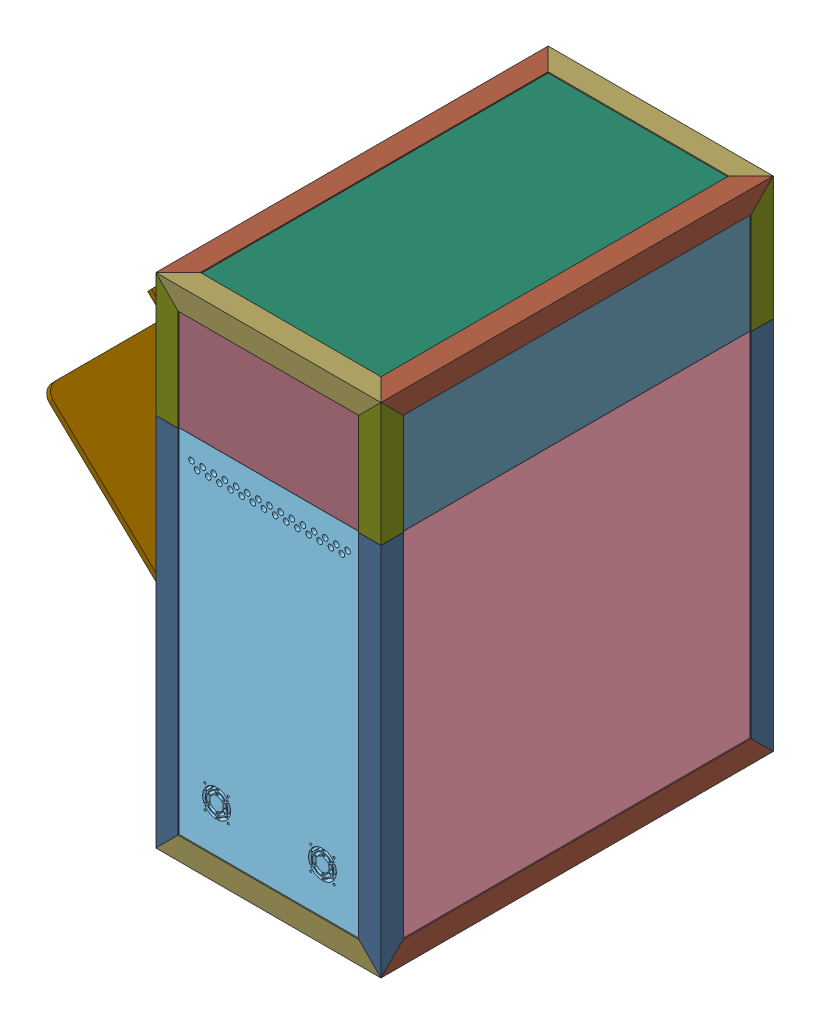
SolidWorks assembly carcasse, configuration Défaut. Lengths in mm.
Overall size (750.58 894.35 704).
60 component instances, 17 part files, 82 mates.
Components (placement in the parent):
- cadre_600x300mm-1: cadre_600x300mm [Défaut] at (-215.194 -19.8636 -400) size (380 40 680)
  - prof_40x40x600mm-1: prof_40x40x600mm [Défaut] at (-14.8937 4.0689 600) size (40 40 600)
  - Rexroth-Default-1: Rexroth-Default [Default] at (-14.8937 24.0689 720) x (0 -1 0) z (-1 0 0) size (40 40 40)
  - prof_40x40x600mm-3: prof_40x40x600mm [Défaut] at (325.1063 4.0689 600) size (40 40 600)
  - Rexroth-Default-3: Rexroth-Default [Default] at (-14.8937 24.0689 80) x (0 -1 0) z (0 0 -1) size (40 40 40)
  - Rexroth-Default-4: Rexroth-Default [Default] at (325.1063 24.0689 80) x (0 -1 0) z (1 0 0) size (40 40 40)
  - Rexroth-Default-5: Rexroth-Default [Default] at (325.1063 24.0689 720) x (0 -1 0) z (0 0 1) size (40 40 40)
  - prof_40x40x300mm-1: prof_40x40x300mm [Défaut] at (105.1063 4.0689 720) x (0 0 1) z (-1 0 0) size (40 40 300)
  - prof_40x40x300mm-2: prof_40x40x300mm [Défaut] at (105.1063 4.0689 80) x (0 0 1) z (-1 0 0) size (40 40 300)
- prof_40x40x600mm-1: prof_40x40x600mm [Défaut] at (109.9123 104.2053 -320) x (1 0 0) z (0 -1 0) size (40 40 600)
- prof_40x40x600mm-2: prof_40x40x600mm [Défaut] at (109.9123 104.2053 320) x (1 0 0) z (0 -1 0) size (40 40 600)
- prof_40x40x600mm-3: prof_40x40x600mm [Défaut] at (-230.0877 104.2053 320) x (1 0 0) z (0 -1 0) size (40 40 600)
- prof_40x40x600mm-4: prof_40x40x600mm [Défaut] at (-230.0877 104.2053 -320) x (1 0 0) z (0 -1 0) size (40 40 600)
- cadre_600x300mm-2: cadre_600x300mm [Défaut] at (95.0186 628.2742 -400) x (-1 0 0) z (0 0 1) size (380 40 680)
  - prof_40x40x600mm-1: prof_40x40x600mm [Défaut] at (-14.8937 4.0689 600) size (40 40 600)
  - Rexroth-Default-1: Rexroth-Default [Default] at (-14.8937 24.0689 720) x (0 -1 0) z (-1 0 0) size (40 40 40)
  - prof_40x40x600mm-3: prof_40x40x600mm [Défaut] at (325.1063 4.0689 600) size (40 40 600)
  - Rexroth-Default-3: Rexroth-Default [Default] at (-14.8937 24.0689 80) x (0 -1 0) z (0 0 -1) size (40 40 40)
  - Rexroth-Default-4: Rexroth-Default [Default] at (325.1063 24.0689 80) x (0 -1 0) z (1 0 0) size (40 40 40)
  - Rexroth-Default-5: Rexroth-Default [Default] at (325.1063 24.0689 720) x (0 -1 0) z (0 0 1) size (40 40 40)
  - prof_40x40x300mm-1: prof_40x40x300mm [Défaut] at (105.1063 4.0689 720) x (0 0 1) z (-1 0 0) size (40 40 300)
  - prof_40x40x300mm-2: prof_40x40x300mm [Défaut] at (105.1063 4.0689 80) x (0 0 1) z (-1 0 0) size (40 40 300)
- prof_40x40x600mm-5: prof_40x40x600mm [Défaut] at (109.9123 134.2053 200) size (40 40 600)
- prof_40x40x600mm-6: prof_40x40x600mm [Défaut] at (-230.0877 134.2053 200) size (40 40 600)
- plaque_acrylique_680x670-2: plaque_acrylique_680x670 [Défaut] at (129.9123 299.2053 0) x (0 0 -1) z (1 0 0) size (680 670 10)
- plaque_acrylique_380x670-1: plaque_acrylique_380x670 [Défaut] at (-60.0877 299.2053 -350) size (380 670 10)
- plaque_acrylique_380x670-2: plaque_acrylique_380x670 [Défaut] at (-60.0877 299.2053 340) size (380 670 10)
- plaque_acrylique_680x670_porte-1: plaque_acrylique_680x670_porte [Défaut] at (-260.0877 299.2053 0) x (0 0 -1) z (1 0 0) size (680 670 10)
- charniere-1: charniere [Défaut] at (-253.7309 154.2053 256.2875) x (0 0 1) z (0 -1 0) size (40 29.08 53.23)
  - axe charnière-1: axe charnière [Défaut] at (-76.2875 9.8568 0) size (40 5 5)
  - batant charnière-1: batant charnière [Défaut] at (-76.2875 10.1991 -17.6196) size (40 7 33.5)
  - batant charnière-2: batant charnière [Défaut] at (-36.2875 -2.6626 12.4029) x (-1 0 0) z (0 0.723942 -0.689861) size (40 7 33.5)
- charniere-2: charniere [Défaut] at (-253.7309 154.2053 -143.7125) x (0 0 1) z (0 -1 0) size (40 29.08 53.23)
  - axe charnière-1: axe charnière [Défaut] at (-76.2875 9.8568 0) size (40 5 5)
  - batant charnière-1: batant charnière [Défaut] at (-76.2875 10.1991 -17.6196) size (40 7 33.5)
  - batant charnière-2: batant charnière [Défaut] at (-36.2875 -2.6626 12.4029) x (-1 0 0) z (0 0.723942 -0.689861) size (40 7 33.5)
- porte-1: porte [Défaut] at (-366.1448 256.769 0) x (0 0 -1) z (0.689861 0.723942 0) size (480 480 10)
- eclisse_40x40x670_bisote_x1-1: eclisse_40x40x670_bisote_x1 [Défaut] at (-242.0877 -37.7947 -331.8864) size (40 672 40)
- eclisse_40x40x670_bisote_x1-2: eclisse_40x40x670_bisote_x1 [Défaut] at (-241.9741 -37.7947 332) x (0 0 -1) z (1 0 0) size (40 672 40)
- eclisse_40x40x670_bisote_x1-3: eclisse_40x40x670_bisote_x1 [Défaut] at (121.9123 -37.7947 331.8864) x (-1 0 0) z (0 0 -1) size (40 672 40)
- eclisse_40x40x670_bisote_x1-4: eclisse_40x40x670_bisote_x1 [Défaut] at (121.7986 -37.7947 -332) x (0 0 1) z (-1 0 0) size (40 672 40)
- eclisse_40x40x704_bisote_x2-1: eclisse_40x40x704_bisote_x2 [Défaut] at (121.7986 -17.7947 352) x (0 1 0) z (-1 0 0) size (40 704 40)
- eclisse_40x40x704_bisote_x2-2: eclisse_40x40x704_bisote_x2 [Défaut] at (-242.0877 -17.681 352) x (1 0 0) z (0 1 0) size (40 704 40)
- eclisse_40x40x404_bisote_x2-1: eclisse_40x40x404_bisote_x2 [Défaut] at (141.9123 -17.681 332) x (0 0 -1) z (0 1 0) size (40 404 40)
- eclisse_40x40x404_bisote_x2-2: eclisse_40x40x404_bisote_x2 [Défaut] at (141.9123 -17.7947 -331.8864) x (0 1 0) z (0 0 1) size (40 404 40)
- couvercle-1: couvercle [Défaut] at (127.4119 748.2742 345) size (404 222 704)
  - plaque_acrylique_380x210-1: plaque_acrylique_380x210 [Défaut] at (-187.4996 -8.7215 -5) size (380 210 10)
  - plaque_acrylique_680x210-1: plaque_acrylique_680x210 [Défaut] at (2.5004 -8.7215 -345) x (0 0 -1) z (1 0 0) size (680 210 10)
  - plaque_acrylique_680x210-2: plaque_acrylique_680x210 [Défaut] at (-387.4996 -8.7215 -345) x (0 0 -1) z (1 0 0) size (680 210 10)
  - plaque_acrylique_380x210-2: plaque_acrylique_380x210 [Défaut] at (-187.4996 -8.7215 -695) size (380 210 10)
  - plaque_acrylique_380x680-1: plaque_acrylique_380x680 [Défaut] at (-187.4996 96.2785 -345) x (1 0 0) z (0 1 0) size (380 680 10)
  - eclisse_40x40x404_bisote_x2-1: eclisse_40x40x404_bisote_x2 [Défaut] at (14.5004 88.1649 -677) x (0 0 1) z (0 -1 0) size (40 404 40)
  - eclisse_40x40x704_bisote_x2-1: eclisse_40x40x704_bisote_x2 [Défaut] at (-5.6132 88.2785 -697) x (0 -1 0) z (-1 0 0) size (40 704 40)
  - eclisse_40x40x404_bisote_x2-2: eclisse_40x40x404_bisote_x2 [Défaut] at (-389.4996 88.1649 -13) x (0 0 -1) z (0 -1 0) size (40 404 40)
  - eclisse_40x40x704_bisote_x2-2: eclisse_40x40x704_bisote_x2 [Défaut] at (-369.4996 88.1649 -697) x (1 0 0) z (0 -1 0) size (40 704 40)
  - eclisse_40x40x222_bisote_x1-1: eclisse_40x40x222_bisote_x1 [Défaut] at (-369.386 108.2785 -677) x (0 0 1) z (1 0 0) size (40 222 40)
  - eclisse_40x40x222_bisote_x1-2: eclisse_40x40x222_bisote_x1 [Défaut] at (-5.4996 108.2785 -676.8864) x (-1 0 0) z (0 0 1) size (40 222 40)
  - eclisse_40x40x222_bisote_x1-3: eclisse_40x40x222_bisote_x1 [Défaut] at (-5.6132 108.2785 -13) x (0 0 -1) z (-1 0 0) size (40 222 40)
  - eclisse_40x40x222_bisote_x1-4: eclisse_40x40x222_bisote_x1 [Défaut] at (-369.4996 108.2785 -13.1136) x (1 0 0) z (0 0 -1) size (40 222 40)
- plaque_repartition_aire_chaud_300x544mm-1: plaque_repartition_aire_chaud_300x544mm [Défaut] at (-60.0936 129.2053 0) x (0 0 -1) z (1 0 0) size (680 10 324)
Mates (geometry in assembly coordinates):
- Coïncidente1: coincident anti-aligned: plane of cadre_600x300mm-1/Rexroth-Default-3 through (-230.0877 4.2053 -320) normal (0 1 0); plane of prof_40x40x600mm-4 through (-213.0877 4.2053 -337) normal (0 -1 0)
- Coïncidente2: coincident anti-aligned: plane of cadre_600x300mm-1/Rexroth-Default-1 through (-230.0877 4.2053 320) normal (0 1 0); plane of prof_40x40x600mm-3 through (-213.0877 4.2053 303) normal (0 -1 0)
- Coïncidente3: coincident anti-aligned: plane of cadre_600x300mm-1/Rexroth-Default-5 through (109.9123 4.2053 320) normal (0 1 0); plane of prof_40x40x600mm-2 through (126.9123 4.2053 303) normal (0 -1 0)
- Coïncidente4: coincident anti-aligned: plane of cadre_600x300mm-1/Rexroth-Default-4 through (109.9123 4.2053 -320) normal (0 1 0); plane of prof_40x40x600mm-1 through (126.9123 4.2053 -337) normal (0 -1 0)
- Coïncidente5: coincident aligned: plane of cadre_600x300mm-1/Rexroth-Default-4 through (129.9123 -15.7947 -320) normal (1 0 0); plane of prof_40x40x600mm-1 through (129.9123 604.2053 -314) normal (1 0 0)
- Coïncidente6: coincident aligned: plane of cadre_600x300mm-1/Rexroth-Default-4 through (109.9123 -15.7947 -340) normal (0 0 -1); plane of prof_40x40x600mm-1 through (115.9123 604.2053 -340) normal (0 0 -1)
- Coïncidente7: coincident aligned: plane of cadre_600x300mm-1/Rexroth-Default-5 through (129.9123 -15.7947 320) normal (1 0 0); plane of prof_40x40x600mm-2 through (129.9123 604.2053 303) normal (1 0 0)
- Coïncidente8: coincident aligned: plane of cadre_600x300mm-1/Rexroth-Default-5 through (109.9123 -15.7947 340) normal (0 0 1); plane of prof_40x40x600mm-2 through (126.9123 604.2053 340) normal (0 0 1)
- Coïncidente9: coincident aligned: plane of cadre_600x300mm-1/Rexroth-Default-1 through (-230.0877 -15.7947 340) normal (0 0 1); plane of prof_40x40x600mm-3 through (-213.0877 604.2053 340) normal (0 0 1)
- Coïncidente10: coincident aligned: plane of cadre_600x300mm-1/Rexroth-Default-1 through (-250.0877 -15.7947 320) normal (-1 0 0); plane of prof_40x40x600mm-3 through (-250.0877 604.2053 337) normal (-1 0 0)
- Coïncidente11: coincident aligned: plane of cadre_600x300mm-1/Rexroth-Default-3 through (-250.0877 -15.7947 -320) normal (-1 0 0); plane of prof_40x40x600mm-4 through (-250.0877 604.2053 -303) normal (-1 0 0)
- Coïncidente12: coincident aligned: plane of cadre_600x300mm-1/Rexroth-Default-3 through (-230.0877 -15.7947 -340) normal (0 0 -1); plane of prof_40x40x600mm-4 through (-247.0877 604.2053 -340) normal (0 0 -1)
- Coïncidente13: coincident anti-aligned: plane of prof_40x40x600mm-1 through (126.9123 604.2053 -337) normal (0 1 0); plane of cadre_600x300mm-2/Rexroth-Default-3 through (109.9123 604.2053 -320) normal (0 -1 0)
- Coïncidente14: coincident aligned: plane of prof_40x40x600mm-3 through (-250.0877 604.2053 337) normal (-1 0 0); plane of cadre_600x300mm-2/Rexroth-Default-5 through (-250.0877 624.2053 320) normal (-1 0 0)
- Coïncidente15: coincident aligned: plane of prof_40x40x600mm-3 through (-236.0877 604.2053 340) normal (0 0 1); plane of cadre_600x300mm-2/Rexroth-Default-5 through (-230.0877 624.2053 340) normal (0 0 1)
- Coïncidente16: coincident anti-aligned: plane of prof_40x40x600mm-4 through (-236.0877 604.2053 -300) normal (0 0 1); plane of prof_40x40x600mm-6 through (-213.0877 117.2053 -300) normal (0 0 -1)
- Coïncidente17: coincident aligned: plane of prof_40x40x600mm-4 through (-250.0877 604.2053 -303) normal (-1 0 0); plane of prof_40x40x600mm-6 through (-250.0877 151.2053 -300) normal (-1 0 0)
- Distance1: distance = 110 mm anti-aligned: plane of prof_40x40x600mm-6 through (-247.0877 114.2053 -300) normal (0 -1 0); plane of cadre_600x300mm-1/prof_40x40x600mm-1 through (-236.0877 4.2053 -300) normal (0 1 0)
- Coïncidente19: coincident aligned: plane of prof_40x40x600mm-1 through (129.9123 604.2053 -314) normal (1 0 0); plane of prof_40x40x600mm-5 through (129.9123 140.2053 -300) normal (1 0 0)
- Coïncidente20: coincident anti-aligned: plane of prof_40x40x600mm-1 through (126.9123 604.2053 -300) normal (0 0 1); plane of prof_40x40x600mm-5 through (126.9123 117.2053 -300) normal (0 0 -1)
- Coïncidente21: coincident aligned: plane of prof_40x40x600mm-5 through (103.9123 154.2053 -300) normal (0 1 0); plane of prof_40x40x600mm-6 through (-213.0877 154.2053 -300) normal (0 1 0)
- Coïncidente22: coincident anti-aligned: plane of prof_40x40x600mm-5 through (89.9123 151.2053 -300) normal (-1 0 0); plane of ? through (89.9123 117.2053 -297) normal (1 0 0)
- Coïncidente23: coincident aligned: plane of prof_40x40x600mm-5 through (103.9123 154.2053 -300) normal (0 1 0); plane of ? through (-210.0877 154.2053 -274) normal (0 1 0)
- Coïncidente24: coincident anti-aligned: plane of prof_40x40x600mm-1 through (103.9123 604.2053 -300) normal (0 0 1); plane of ? through (-210.0877 140.2053 -300) normal (0 0 -1)
- Coïncidente29: coincident aligned: plane of ? through (-210.0877 154.2053 -103.667) normal (0 1 0); plane of prof_40x40x600mm-5 through (103.9123 154.2053 -300) normal (0 1 0)
- Coïncidente31: coincident anti-aligned: plane of ? through (89.9123 117.2053 -103.667) normal (1 0 0); plane of prof_40x40x600mm-5 through (89.9123 151.2053 -300) normal (-1 0 0)
- Distance2: distance = 153.333 mm anti-aligned: plane of ? through (-210.0877 140.2053 -106.667) normal (0 0 -1); plane of ? through (-210.0877 151.2053 -260) normal (0 0 1)
- Coïncidente34: coincident anti-aligned: plane of cadre_600x300mm-2/prof_40x40x600mm-3 through (-250.0877 641.2053 -300) normal (-1 0 0); plane of plaque_acrylique_680x670_porte-1 through (-250.0877 299.2053 0) normal (1 0 0)
- Coïncidente36: coincident aligned: plane of cadre_600x300mm-1/prof_40x40x600mm-1 through (-247.0877 -35.7947 -300) normal (0 -1 0); plane of plaque_acrylique_680x670_porte-1 through (-250.0877 -35.7947 340) normal (0 -1 0)
- Coïncidente37: coincident aligned: plane of prof_40x40x600mm-3 through (-236.0877 604.2053 340) normal (0 0 1); plane of plaque_acrylique_680x670_porte-1 through (-250.0877 634.2053 340) normal (0 0 1)
- Coïncidente38: coincident anti-aligned: plane of cadre_600x300mm-2/prof_40x40x600mm-1 through (129.9123 630.2053 -300) normal (1 0 0); plane of plaque_acrylique_680x670-2 through (129.9123 299.2053 0) normal (-1 0 0)
- Coïncidente39: coincident aligned: plane of prof_40x40x600mm-2 through (126.9123 604.2053 340) normal (0 0 1); plane of plaque_acrylique_680x670-2 through (139.9123 634.2053 340) normal (0 0 1)
- Coïncidente40: coincident aligned: plane of cadre_600x300mm-1/prof_40x40x600mm-3 through (115.9123 -35.7947 -300) normal (0 -1 0); plane of plaque_acrylique_680x670-2 through (139.9123 -35.7947 340) normal (0 -1 0)
- Coïncidente41: coincident anti-aligned: plane of prof_40x40x600mm-3 through (-213.0877 604.2053 340) normal (0 0 1); plane of plaque_acrylique_380x670-2 through (-60.0877 299.2053 340) normal (0 0 -1)
- Coïncidente42: coincident aligned: plane of cadre_600x300mm-2/Rexroth-Default-5 through (-250.0877 624.2053 320) normal (-1 0 0); plane of plaque_acrylique_380x670-2 through (-250.0877 634.2053 350) normal (-1 0 0)
- Coïncidente43: coincident aligned: plane of cadre_600x300mm-1/prof_40x40x300mm-1 through (89.9123 -35.7947 326) normal (0 -1 0); plane of plaque_acrylique_380x670-2 through (-250.0877 -35.7947 350) normal (0 -1 0)
- Coïncidente44: coincident aligned: plane of cadre_600x300mm-1/prof_40x40x300mm-2 through (89.9123 -35.7947 -337) normal (0 -1 0); plane of plaque_acrylique_380x670-1 through (-250.0877 -35.7947 -340) normal (0 -1 0)
- Coïncidente45: coincident aligned: plane of cadre_600x300mm-2/Rexroth-Default-4 through (-250.0877 624.2053 -320) normal (-1 0 0); plane of plaque_acrylique_380x670-1 through (-250.0877 634.2053 -340) normal (-1 0 0)
- Coïncidente46: coincident anti-aligned: plane of prof_40x40x600mm-4 through (-247.0877 604.2053 -340) normal (0 0 -1); plane of plaque_acrylique_380x670-1 through (-60.0877 299.2053 -340) normal (0 0 1)
- Coïncidente47: coincident anti-aligned: plane of prof_40x40x600mm-6 through (-250.0877 151.2053 -300) normal (-1 0 0); plane of plaque_acrylique_680x670_porte-1 through (-250.0877 299.2053 0) normal (1 0 0)
- Coïncidente48: coincident aligned: plane of cadre_600x300mm-2/Rexroth-Default-5 through (-230.0877 624.2053 340) normal (0 0 1); plane of plaque_acrylique_680x670_porte-1 through (-250.0877 634.2053 340) normal (0 0 1)
- Coïncidente49: coincident aligned: plane of cadre_600x300mm-1/prof_40x40x600mm-1 through (-247.0877 -35.7947 -300) normal (0 -1 0); plane of plaque_acrylique_680x670_porte-1 through (-250.0877 -35.7947 340) normal (0 -1 0)
- Coïncidente50: coincident anti-aligned: plane of plaque_acrylique_680x670_porte-1 through (-260.0877 299.2053 0) normal (-1 0 0); plane of charniere-1/batant charnière-1 through (-260.0877 114.2053 220) normal (1 0 0)
- Coïncidente51: coincident anti-aligned: plane of plaque_acrylique_680x670_porte-1 through (-260.0877 299.2053 0) normal (-1 0 0); plane of charniere-2/batant charnière-1 through (-260.0877 114.2053 -180) normal (1 0 0)
- Distance4: distance = 20 mm anti-aligned: plane of charniere-2/batant charnière-1 through (-263.5877 154.2053 -220) normal (0 0 -1); plane of plaque_acrylique_680x670_porte-1 through (-260.0877 574.2053 -240) normal (0 0 1)
- Coïncidente54: coincident aligned: line of plaque_acrylique_680x670_porte-1 through (-260.0877 154.2053 220) axis (0 0 -1); line of charniere-2/batant charnière-1 through (-260.0877 154.2053 -180) axis (0 0 -1)
- Distance5: distance = 20 mm anti-aligned: plane of plaque_acrylique_680x670_porte-1 through (-260.0877 574.2053 240) normal (0 0 -1); plane of charniere-1/batant charnière-1 through (-263.5877 154.2053 220) normal (0 0 1)
- Coïncidente57: coincident aligned: line of plaque_acrylique_680x670_porte-1 through (-260.0877 154.2053 220) axis (0 0 -1); line of charniere-1/batant charnière-1 through (-260.0877 154.2053 220) axis (0 0 -1)
- Coïncidente62: coincident anti-aligned: plane of charniere-1/batant charnière-2 through (-290.1309 184.3336 180) normal (0.689861 0.723942 0); plane of porte-1 through (-586.947 467.1766 30) normal (-0.689861 -0.723942 0)
- Coïncidente63: coincident anti-aligned: line of charniere-1/batant charnière-2 through (-261.1732 156.7391 200) axis (0 0 1); line of porte-1 through (-261.1732 156.7391 220) axis (0 0 -1)
- Coïncidente64: coincident anti-aligned: plane of plaque_acrylique_680x670_porte-1 through (-260.0877 574.2053 240) normal (0 0 -1); plane of porte-1 through (-558.3301 453.7202 240) normal (0 0 1)
- Coïncidente65: coincident anti-aligned: plane of plaque_acrylique_380x670-1 through (-60.0877 299.2053 -350) normal (0 0 -1); plane of eclisse_40x40x670_bisote_x1-1 through (-260.0877 634.2053 -350) normal (0 0 1)
- Coïncidente66: coincident anti-aligned: plane of plaque_acrylique_680x670_porte-1 through (-260.0877 299.2053 0) normal (-1 0 0); plane of eclisse_40x40x670_bisote_x1-1 through (-260.0877 634.2053 -350) normal (1 0 0)
- Coïncidente67: coincident aligned: plane of plaque_acrylique_680x670_porte-1 through (-250.0877 634.2053 340) normal (0 1 0); plane of eclisse_40x40x670_bisote_x1-1 through (-242.0877 634.2053 -331.8864) normal (0 1 0)
- Coïncidente68: coincident anti-aligned: plane of plaque_acrylique_680x670-2 through (139.9123 299.2053 0) normal (1 0 0); plane of eclisse_40x40x670_bisote_x1-4 through (139.9123 634.2053 -350) normal (-1 0 0)
- Coïncidente69: coincident anti-aligned: plane of plaque_acrylique_380x670-1 through (-60.0877 299.2053 -350) normal (0 0 -1); plane of eclisse_40x40x670_bisote_x1-4 through (139.9123 634.2053 -350) normal (0 0 1)
- Coïncidente70: coincident aligned: plane of plaque_acrylique_380x670-1 through (-250.0877 634.2053 -340) normal (0 1 0); plane of eclisse_40x40x670_bisote_x1-4 through (121.7986 634.2053 -332) normal (0 1 0)
- Coïncidente71: coincident anti-aligned: plane of plaque_acrylique_380x670-2 through (-60.0877 299.2053 350) normal (0 0 1); plane of eclisse_40x40x670_bisote_x1-2 through (-260.0877 634.2053 350) normal (0 0 -1)
- Coïncidente72: coincident anti-aligned: plane of plaque_acrylique_680x670_porte-1 through (-260.0877 299.2053 0) normal (-1 0 0); plane of eclisse_40x40x670_bisote_x1-2 through (-260.0877 634.2053 350) normal (1 0 0)
- Coïncidente73: coincident aligned: plane of plaque_acrylique_380x670-2 through (-250.0877 634.2053 350) normal (0 1 0); plane of eclisse_40x40x670_bisote_x1-2 through (-241.9741 634.2053 332) normal (0 1 0)
- Coïncidente74: coincident anti-aligned: plane of plaque_acrylique_680x670-2 through (139.9123 299.2053 0) normal (1 0 0); plane of eclisse_40x40x670_bisote_x1-3 through (139.9123 634.2053 350) normal (-1 0 0)
- Coïncidente75: coincident anti-aligned: plane of plaque_acrylique_380x670-2 through (-60.0877 299.2053 350) normal (0 0 1); plane of eclisse_40x40x670_bisote_x1-3 through (139.9123 634.2053 350) normal (0 0 -1)
- Coïncidente76: coincident aligned: plane of plaque_acrylique_380x670-2 through (-250.0877 634.2053 350) normal (0 1 0); plane of eclisse_40x40x670_bisote_x1-3 through (121.9123 634.2053 331.8864) normal (0 1 0)
- Coïncidente77: coincident anti-aligned: plane of eclisse_40x40x670_bisote_x1-1 through (327.9123 -37.7947 -352) normal (0 -0.707107 0.707107); plane of eclisse_40x40x704_bisote_x2-2 through (-222.0877 -37.7947 -352) normal (0 0.707107 -0.707107)
- Coïncidente78: coincident aligned: plane of eclisse_40x40x670_bisote_x1-1 through (-262.0877 634.2053 -352) normal (-1 0 0); plane of eclisse_40x40x704_bisote_x2-2 through (-262.0877 -37.7947 -352) normal (-1 0 0)
- Coïncidente79: coincident anti-aligned: plane of eclisse_40x40x670_bisote_x1-2 through (327.9123 -37.7947 352) normal (0 -0.707107 -0.707107); plane of eclisse_40x40x704_bisote_x2-2 through (327.9123 -37.7947 352) normal (0 0.707107 0.707107)
- Coïncidente80: coincident anti-aligned: plane of eclisse_40x40x670_bisote_x1-4 through (-448.0877 -37.7947 -352) normal (0 -0.707107 0.707107); plane of eclisse_40x40x704_bisote_x2-1 through (101.9123 -37.7947 -352) normal (0 0.707107 -0.707107)
- Coïncidente81: coincident aligned: plane of eclisse_40x40x670_bisote_x1-4 through (141.9123 634.2053 -352) normal (1 0 0); plane of eclisse_40x40x704_bisote_x2-1 through (141.9123 -37.7947 -352) normal (1 0 0)
- Coïncidente82: coincident anti-aligned: plane of eclisse_40x40x670_bisote_x1-3 through (-448.0877 -37.7947 352) normal (0 -0.707107 -0.707107); plane of eclisse_40x40x704_bisote_x2-1 through (-448.0877 -37.7947 352) normal (0 0.707107 0.707107)
- Coïncidente86: coincident aligned: plane of eclisse_40x40x704_bisote_x2-1 through (141.9123 -37.7947 -352) normal (0 -1 0); plane of eclisse_40x40x404_bisote_x2-1 through (-262.0877 -37.7947 352) normal (0 -1 0)
- Coïncidente87: coincident aligned: plane of eclisse_40x40x670_bisote_x1-3 through (141.9123 634.2053 352) normal (0 0 1); plane of eclisse_40x40x404_bisote_x2-1 through (-262.0877 -37.7947 352) normal (0 0 1)
- Coïncidente88: coincident anti-aligned: plane of eclisse_40x40x670_bisote_x1-2 through (-262.0877 -37.7947 -238) normal (0.707107 -0.707107 0); plane of eclisse_40x40x404_bisote_x2-1 through (-262.0877 -37.7947 312) normal (-0.707107 0.707107 0)
- Coïncidente89: coincident aligned: plane of eclisse_40x40x670_bisote_x1-1 through (-262.0877 634.2053 -352) normal (0 0 -1); plane of eclisse_40x40x404_bisote_x2-2 through (-262.0877 -37.7947 -352) normal (0 0 -1)
- Coïncidente90: coincident aligned: plane of eclisse_40x40x704_bisote_x2-1 through (141.9123 -37.7947 -352) normal (0 -1 0); plane of eclisse_40x40x404_bisote_x2-2 through (-262.0877 -37.7947 -352) normal (0 -1 0)
- Coïncidente91: coincident anti-aligned: plane of eclisse_40x40x670_bisote_x1-1 through (-262.0877 -37.7947 238) normal (0.707107 -0.707107 0); plane of eclisse_40x40x404_bisote_x2-2 through (-262.0877 -37.7947 -312) normal (-0.707107 0.707107 0)
- Coïncidente92: coincident aligned: plane of eclisse_40x40x670_bisote_x1-1 through (-262.0877 634.2053 -352) normal (-1 0 0); plane of couvercle-1/eclisse_40x40x222_bisote_x1-1 through (-262.0877 634.5527 -352) normal (-1 0 0)
- Coïncidente93: coincident aligned: plane of eclisse_40x40x670_bisote_x1-1 through (-262.0877 634.2053 -352) normal (0 0 -1); plane of couvercle-1/eclisse_40x40x222_bisote_x1-1 through (-262.0877 634.5527 -352) normal (0 0 -1)
- Distance6: distance = 140 mm anti-aligned: plane of ? through (29.9123 579.2053 -200) normal (0 0 -1); plane of plaque_acrylique_380x670-1 through (-60.0877 299.2053 -340) normal (0 0 1)
- Distance7: distance = 100 mm anti-aligned: plane of ? through (29.9123 579.2053 -200) normal (1 0 0); plane of plaque_acrylique_680x670-2 through (129.9123 299.2053 0) normal (-1 0 0)
- Coïncidente98: coincident: line of prof_40x40x600mm-6 through (-222.0936 134.5117 -300) axis (0 0 1); plane of plaque_repartition_aire_chaud_300x544mm-1 through (-222.0936 139.2053 300) normal (-1 0 0)
- Coïncidente99: coincident anti-aligned: plane of prof_40x40x600mm-6 through (-211.0877 129.2053 -300) normal (0 1 0); plane of plaque_repartition_aire_chaud_300x544mm-1 through (-60.0936 129.2053 0) normal (0 -1 0)
- Coïncidente100: coincident anti-aligned: plane of plaque_acrylique_380x670-2 through (-60.0877 299.2053 340) normal (0 0 -1); plane of plaque_repartition_aire_chaud_300x544mm-1 through (-210.0936 139.2053 340) normal (0 0 1)
